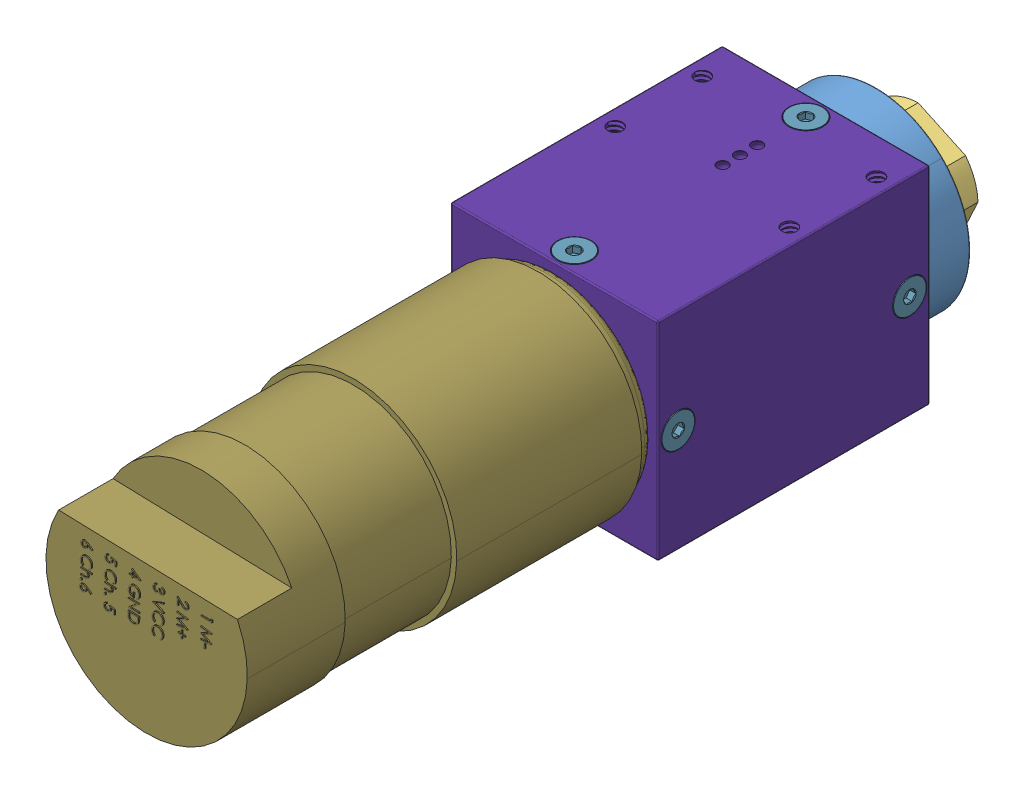
SolidWorks assembly am-3643 NeveRest Sport, 104-1 with Motor, configuration Default. Lengths in mm.
Overall size (48.85 48.85 145.31).
41 component instances, 19 part files, 0 mates.
Components (placement in the parent):
- am-3643 NeveRest Sport, 104-1 with Motor(2)^am-3643 NeveRest Sport, 104-1 with Motor-1: am-3643 NeveRest Sport, 104-1 with Motor(2)^am-3643 NeveRest Sport, 104-1 with Motor [Default] at origin size (48.85 48.85 145.31) (virtual)
  - dv-XXXX Output Plug - 550 Sport^am-3643 NeveRest Sport, 104-1 with Motor(2)_am-3643 NeveRest Sport, 104-1 with Motor-1: dv-XXXX Output Plug - 550 Sport^am-3643 NeveRest Sport, 104-1 with Motor(2)_am-3643 NeveRest Sport, 104-1 with Motor [Default] at (30.7788 -45.9281 37.6212) x (-0.707107 -0.707107 0) z (0 0 1) size (34.54 34.54 34.87) (virtual)
    - dv-XXXX Output Plug with orbital bolt circle^dv-XXXX Output Plug - 550 Sport_am-3643 NeveRest Sport, 104-1 with Motor(2)_am-3643 NeveRest Sport, 104-1 with Motor-1: dv-XXXX Output Plug with orbital bolt circle^dv-XXXX Output Plug - 550 Sport_am-3643 NeveRest Sport, 104-1 with Motor(2)_am-3643 NeveRest Sport, 104-1 with Motor [Default] at (-7.0244 -4.5434 5.3964) size (34.54 34.54 17.78) (virtual)
    - BALL BEARING_5972K154^dv-XXXX Output Plug - 550 Sport_am-3643 NeveRest Sport, 104-1 with Motor(2)_am-3643 NeveRest Sport, 104-1 with Motor-1: BALL BEARING_5972K154^dv-XXXX Output Plug - 550 Sport_am-3643 NeveRest Sport, 104-1 with Motor(2)_am-3643 NeveRest Sport, 104-1 with Motor [Default] at (-7.0244 -4.5434 -0.8666) size (21 21 5) (virtual)
    - BALL BEARING_5972K154^dv-XXXX Output Plug - 550 Sport_am-3643 NeveRest Sport, 104-1 with Motor(2)_am-3643 NeveRest Sport, 104-1 with Motor-2: BALL BEARING_5972K154^dv-XXXX Output Plug - 550 Sport_am-3643 NeveRest Sport, 104-1 with Motor(2)_am-3643 NeveRest Sport, 104-1 with Motor [Default] at (-7.0244 -4.5434 10.1354) size (21 21 5) (virtual)
    - Nub Shaft^dv-XXXX Output Plug - 550 Sport_am-3643 NeveRest Sport, 104-1 with Motor(2)_am-3643 NeveRest Sport, 104-1 with Motor-1: Nub Shaft^dv-XXXX Output Plug - 550 Sport_am-3643 NeveRest Sport, 104-1 with Motor(2)_am-3643 NeveRest Sport, 104-1 with Motor [Default] at (-7.0244 -4.5434 20.2536) x (-0.939267 -0.343187 0) z (0.343187 -0.939267 0) size (19.05 34.87 19.05) (virtual)
  - dv-XXXX Carrier Stage 4-1 Planet, 5-1 Sun - 550 Sport^am-3643 NeveRest Sport, 104-1 with Motor(2)_am-3643 NeveRest Sport, 104-1 with Motor-1: dv-XXXX Carrier Stage 4-1 Planet, 5-1 Sun - 550 Sport^am-3643 NeveRest Sport, 104-1 with Motor(2)_am-3643 NeveRest Sport, 104-1 with Motor [Default] at (63.7059 -27.5277 100.4568) x (0.941837 -0.336071 0) z (-0.336071 -0.941837 0) size (29.23 15.47 28.59) (virtual)
    - am-2892+15T+pinion+3.2mm+bore^dv-XXXX Carrier Stage 4-1 Planet, 5-1 Sun - 550 Sport_am-3643 NeveRest Sport, 104-1 with Motor(2)_am-3643 NeveRest Sport, 104-1 with Motor-1: am-2892+15T+pinion+3.2mm+bore^dv-XXXX Carrier Stage 4-1 Planet, 5-1 Sun - 550 Sport_am-3643 NeveRest Sport, 104-1 with Motor(2)_am-3643 NeveRest Sport, 104-1 with Motor [Default] at (-25.9249 -17.3194 11.1026) x (0 -1 0) z (0.056322 0 -0.998413) size (5.31 10.12 10.18) (virtual)
    - am-2892+15T+pinion+3.2mm+bore^dv-XXXX Carrier Stage 4-1 Planet, 5-1 Sun - 550 Sport_am-3643 NeveRest Sport, 104-1 with Motor(2)_am-3643 NeveRest Sport, 104-1 with Motor-2: am-2892+15T+pinion+3.2mm+bore^dv-XXXX Carrier Stage 4-1 Planet, 5-1 Sun - 550 Sport_am-3643 NeveRest Sport, 104-1 with Motor(2)_am-3643 NeveRest Sport, 104-1 with Motor [Default] at (-16.9249 -17.3194 20.1026) x (0 -1 0) z (-0.169038 0 -0.98561) size (5.31 10.12 10.18) (virtual)
    - am-2892+15T+pinion+3.2mm+bore^dv-XXXX Carrier Stage 4-1 Planet, 5-1 Sun - 550 Sport_am-3643 NeveRest Sport, 104-1 with Motor(2)_am-3643 NeveRest Sport, 104-1 with Motor-3: am-2892+15T+pinion+3.2mm+bore^dv-XXXX Carrier Stage 4-1 Planet, 5-1 Sun - 550 Sport_am-3643 NeveRest Sport, 104-1 with Motor(2)_am-3643 NeveRest Sport, 104-1 with Motor [Default] at (-25.9249 -17.3194 29.1026) x (0 -1 0) z (-0.027474 0 -0.999623) size (5.31 10.12 10.18) (virtual)
    - am-2892+15T+pinion+3.2mm+bore^dv-XXXX Carrier Stage 4-1 Planet, 5-1 Sun - 550 Sport_am-3643 NeveRest Sport, 104-1 with Motor(2)_am-3643 NeveRest Sport, 104-1 with Motor-4: am-2892+15T+pinion+3.2mm+bore^dv-XXXX Carrier Stage 4-1 Planet, 5-1 Sun - 550 Sport_am-3643 NeveRest Sport, 104-1 with Motor(2)_am-3643 NeveRest Sport, 104-1 with Motor [Default] at (-34.9249 -17.3194 20.1026) x (0 -1 0) z (-0.064746 0 -0.997902) size (5.31 10.12 10.18) (virtual)
    - dv-XXXX - Carrier Plate 4-1 Planet, 5-1 Sun^dv-XXXX Carrier Stage 4-1 Planet, 5-1 Sun - 550 Sport_am-3643 NeveRest Sport, 104-1 with Motor(2)_am-3643 NeveRest Sport, 104-1 with Motor-1: dv-XXXX - Carrier Plate 4-1 Planet, 5-1 Sun^dv-XXXX Carrier Stage 4-1 Planet, 5-1 Sun - 550 Sport_am-3643 NeveRest Sport, 104-1 with Motor(2)_am-3643 NeveRest Sport, 104-1 with Motor [Default] at (-25.9249 -27.154 20.1026) size (25.04 10 25.04) (virtual)
    - 11T+pinion+3.2mm+bore^dv-XXXX Carrier Stage 4-1 Planet, 5-1 Sun - 550 Sport_am-3643 NeveRest Sport, 104-1 with Motor(2)_am-3643 NeveRest Sport, 104-1 with Motor-1: 11T+pinion+3.2mm+bore^dv-XXXX Carrier Stage 4-1 Planet, 5-1 Sun - 550 Sport_am-3643 NeveRest Sport, 104-1 with Motor(2)_am-3643 NeveRest Sport, 104-1 with Motor [Default] at (-25.9249 -22.6277 20.1026) x (0 -1 0) z (-0.988725 0 -0.149745) size (10 7.67 7.74) (virtual)
  - dv-XXXX Carrier Stage 5-1 Planet, 5-1 Sun^am-3643 NeveRest Sport, 104-1 with Motor(2)_am-3643 NeveRest Sport, 104-1 with Motor-1: dv-XXXX Carrier Stage 5-1 Planet, 5-1 Sun^am-3643 NeveRest Sport, 104-1 with Motor(2)_am-3643 NeveRest Sport, 104-1 with Motor [Default] at (6.8131 -34.6705 55.7021) x (-0.996841 0.079427 0) z (0.079427 0.996841 0) size (29.78 15.47 28.75) (virtual)
    - dv-XXXX - Carrier Plate 5-1 Planet, 5-1 Sun^dv-XXXX Carrier Stage 5-1 Planet, 5-1 Sun_am-3643 NeveRest Sport, 104-1 with Motor(2)_am-3643 NeveRest Sport, 104-1 with Motor-1: dv-XXXX - Carrier Plate 5-1 Planet, 5-1 Sun^dv-XXXX Carrier Stage 5-1 Planet, 5-1 Sun_am-3643 NeveRest Sport, 104-1 with Motor(2)_am-3643 NeveRest Sport, 104-1 with Motor [Default] at (-26.6144 7.6007 0.9439) size (25.04 10 25.04) (virtual)
    - 17T+pinion+3.2mm+bore^dv-XXXX Carrier Stage 5-1 Planet, 5-1 Sun_am-3643 NeveRest Sport, 104-1 with Motor(2)_am-3643 NeveRest Sport, 104-1 with Motor-1: 17T+pinion+3.2mm+bore^dv-XXXX Carrier Stage 5-1 Planet, 5-1 Sun_am-3643 NeveRest Sport, 104-1 with Motor(2)_am-3643 NeveRest Sport, 104-1 with Motor [Default] at (-35.0144 12.127 0.9439) x (0 1 0) z (-0.112997 0 0.993595) size (5.31 11.33 11.37) (virtual)
    - 17T+pinion+3.2mm+bore^dv-XXXX Carrier Stage 5-1 Planet, 5-1 Sun_am-3643 NeveRest Sport, 104-1 with Motor(2)_am-3643 NeveRest Sport, 104-1 with Motor-2: 17T+pinion+3.2mm+bore^dv-XXXX Carrier Stage 5-1 Planet, 5-1 Sun_am-3643 NeveRest Sport, 104-1 with Motor(2)_am-3643 NeveRest Sport, 104-1 with Motor [Default] at (-26.6144 12.127 9.3439) x (0 1 0) z (0.065842 0 0.99783) size (5.31 11.33 11.37) (virtual)
    - 17T+pinion+3.2mm+bore^dv-XXXX Carrier Stage 5-1 Planet, 5-1 Sun_am-3643 NeveRest Sport, 104-1 with Motor(2)_am-3643 NeveRest Sport, 104-1 with Motor-3: 17T+pinion+3.2mm+bore^dv-XXXX Carrier Stage 5-1 Planet, 5-1 Sun_am-3643 NeveRest Sport, 104-1 with Motor(2)_am-3643 NeveRest Sport, 104-1 with Motor [Default] at (-26.6144 12.127 -7.4561) x (0 1 0) z (0.038378 0 0.999263) size (5.31 11.33 11.37) (virtual)
    - 17T+pinion+3.2mm+bore^dv-XXXX Carrier Stage 5-1 Planet, 5-1 Sun_am-3643 NeveRest Sport, 104-1 with Motor(2)_am-3643 NeveRest Sport, 104-1 with Motor-4: 17T+pinion+3.2mm+bore^dv-XXXX Carrier Stage 5-1 Planet, 5-1 Sun_am-3643 NeveRest Sport, 104-1 with Motor(2)_am-3643 NeveRest Sport, 104-1 with Motor [Default] at (-18.2144 12.127 0.9439) x (0 1 0) z (0.205012 0 0.978759) size (5.31 11.33 11.37) (virtual)
    - 13T+pinion+3.2mm+bore^dv-XXXX Carrier Stage 5-1 Planet, 5-1 Sun_am-3643 NeveRest Sport, 104-1 with Motor(2)_am-3643 NeveRest Sport, 104-1 with Motor-1: 13T+pinion+3.2mm+bore^dv-XXXX Carrier Stage 5-1 Planet, 5-1 Sun_am-3643 NeveRest Sport, 104-1 with Motor(2)_am-3643 NeveRest Sport, 104-1 with Motor [Default] at (-26.6144 12.127 0.9439) x (0 -1 0) z (-0.984718 0 0.174154) size (10 8.9 8.96) (virtual)
  - dv-XXXX Carrier Stage 5-1 Planet, 0.3125 hex output^am-3643 NeveRest Sport, 104-1 with Motor(2)_am-3643 NeveRest Sport, 104-1 with Motor-1: dv-XXXX Carrier Stage 5-1 Planet, 0.3125 hex output^am-3643 NeveRest Sport, 104-1 with Motor(2)_am-3643 NeveRest Sport, 104-1 with Motor [Default] at (38.8348 -52.014 37.7173) x (0.574594 -0.818439 0) z (-0.818439 -0.574594 0) size (30.46 10 28.73) (virtual)
    - dv-XXXX - Carrier Plate 5-1 Planet, 0.3125 hex output^dv-XXXX Carrier Stage 5-1 Planet, 0.3125 hex output_am-3643 NeveRest Sport, 104-1 with Motor(2)_am-3643 NeveRest Sport, 104-1 with Motor-1: dv-XXXX - Carrier Plate 5-1 Planet, 0.3125 hex output^dv-XXXX Carrier Stage 5-1 Planet, 0.3125 hex output_am-3643 NeveRest Sport, 104-1 with Motor(2)_am-3643 NeveRest Sport, 104-1 with Motor [Default] at (-16.3468 15.5854 -4.8585) size (25.04 10 25.04) (virtual)
    - 17T+pinion+3.2mm+bore^dv-XXXX Carrier Stage 5-1 Planet, 0.3125 hex output_am-3643 NeveRest Sport, 104-1 with Motor(2)_am-3643 NeveRest Sport, 104-1 with Motor-1: 17T+pinion+3.2mm+bore^dv-XXXX Carrier Stage 5-1 Planet, 0.3125 hex output_am-3643 NeveRest Sport, 104-1 with Motor(2)_am-3643 NeveRest Sport, 104-1 with Motor [Default] at (-24.7468 20.1117 -4.8585) x (0 1 0) z (0.867721 0 0.497051) size (5.31 11.33 11.37) (virtual)
    - 17T+pinion+3.2mm+bore^dv-XXXX Carrier Stage 5-1 Planet, 0.3125 hex output_am-3643 NeveRest Sport, 104-1 with Motor(2)_am-3643 NeveRest Sport, 104-1 with Motor-2: 17T+pinion+3.2mm+bore^dv-XXXX Carrier Stage 5-1 Planet, 0.3125 hex output_am-3643 NeveRest Sport, 104-1 with Motor(2)_am-3643 NeveRest Sport, 104-1 with Motor [Default] at (-16.3468 20.1117 3.5415) x (0 1 0) z (-0.061129 0 0.99813) size (5.31 11.33 11.37) (virtual)
    - 17T+pinion+3.2mm+bore^dv-XXXX Carrier Stage 5-1 Planet, 0.3125 hex output_am-3643 NeveRest Sport, 104-1 with Motor(2)_am-3643 NeveRest Sport, 104-1 with Motor-3: 17T+pinion+3.2mm+bore^dv-XXXX Carrier Stage 5-1 Planet, 0.3125 hex output_am-3643 NeveRest Sport, 104-1 with Motor(2)_am-3643 NeveRest Sport, 104-1 with Motor [Default] at (-16.3468 20.1117 -13.2585) x (0 1 0) z (0.038378 0 0.999263) size (5.31 11.33 11.37) (virtual)
    - 17T+pinion+3.2mm+bore^dv-XXXX Carrier Stage 5-1 Planet, 0.3125 hex output_am-3643 NeveRest Sport, 104-1 with Motor(2)_am-3643 NeveRest Sport, 104-1 with Motor-4: 17T+pinion+3.2mm+bore^dv-XXXX Carrier Stage 5-1 Planet, 0.3125 hex output_am-3643 NeveRest Sport, 104-1 with Motor(2)_am-3643 NeveRest Sport, 104-1 with Motor [Default] at (-7.9468 20.1117 -4.8585) x (0 1 0) z (0.040503 0 0.999179) size (5.31 11.33 11.37) (virtual)
  - neveRest+15T+pinion^am-3643 NeveRest Sport, 104-1 with Motor(2)_am-3643 NeveRest Sport, 104-1 with Motor-1: neveRest+15T+pinion^am-3643 NeveRest Sport, 104-1 with Motor(2)_am-3643 NeveRest Sport, 104-1 with Motor [Default] at (-29.3619 -57.8483 143.121) x (-0.999543 0.030232 0) z (0 0 -1) size (38 38 89.79) (virtual)
    - am-3104 NeveRest Motor^neveRest+15T+pinion_am-3643 NeveRest Sport, 104-1 with Motor(2)_am-3643 NeveRest Sport, 104-1 with Motor-1: am-3104 NeveRest Motor^neveRest+15T+pinion_am-3643 NeveRest Sport, 104-1 with Motor(2)_am-3643 NeveRest Sport, 104-1 with Motor [Default] at (-61.259 21.9619 50.009) size (38 38 85.19) (virtual)
    - 15T+pinion+3.2mm+bore+motor^neveRest+15T+pinion_am-3643 NeveRest Sport, 104-1 with Motor(2)_am-3643 NeveRest Sport, 104-1 with Motor-1: 15T+pinion+3.2mm+bore+motor^neveRest+15T+pinion_am-3643 NeveRest Sport, 104-1 with Motor(2)_am-3643 NeveRest Sport, 104-1 with Motor [Default] at (-61.259 21.9619 54.7947) x (0 0 1) z (-0.930076 -0.367368 0) size (9.81 10.12 10.18) (virtual)
  - 91294A126_BLACK ALLOY STEEL FLAT-HEAD SOCKET CAP SCREW_91294A126^am-3643 NeveRest Sport, 104-1 with Motor(2)_am-3643 NeveRest Sport, 104-1 with Motor-1: 91294A126_BLACK ALLOY STEEL FLAT-HEAD SOCKET CAP SCREW_91294A126^am-3643 NeveRest Sport, 104-1 with Motor(2)_am-3643 NeveRest Sport, 104-1 with Motor [Default] at (13.433 -37.7484 46.9556) x (0 0 1) z (-1 0 0) size (6 6 6.01) (virtual)
  - Thrust Washer^am-3643 NeveRest Sport, 104-1 with Motor(2)_am-3643 NeveRest Sport, 104-1 with Motor-1: Thrust Washer^am-3643 NeveRest Sport, 104-1 with Motor(2)_am-3643 NeveRest Sport, 104-1 with Motor [Default] at (32.533 -37.7484 84.9184) x (0.422278 0.906466 0) z (0 0 -1) size (28.45 28.45 0.51) (virtual)
  - dv-XXXX Motor Mount Plug^am-3643 NeveRest Sport, 104-1 with Motor(2)_am-3643 NeveRest Sport, 104-1 with Motor-1: dv-XXXX Motor Mount Plug^am-3643 NeveRest Sport, 104-1 with Motor(2)_am-3643 NeveRest Sport, 104-1 with Motor [Default] at (32.533 -37.7484 93.1201) x (-0.707107 0.707107 0) z (0 0 -1) size (30.99 30.99 8.13) (virtual)
  - 91294A126_BLACK ALLOY STEEL FLAT-HEAD SOCKET CAP SCREW_91294A126^am-3643 NeveRest Sport, 104-1 with Motor(2)_am-3643 NeveRest Sport, 104-1 with Motor-2: 91294A126_BLACK ALLOY STEEL FLAT-HEAD SOCKET CAP SCREW_91294A126^am-3643 NeveRest Sport, 104-1 with Motor(2)_am-3643 NeveRest Sport, 104-1 with Motor [Default] at (32.533 -18.6484 89.5006) x (0.466078 0 0.884744) z (0 1 0) size (6 6 6.01) (virtual)
  - 91294A126_BLACK ALLOY STEEL FLAT-HEAD SOCKET CAP SCREW_91294A126^am-3643 NeveRest Sport, 104-1 with Motor(2)_am-3643 NeveRest Sport, 104-1 with Motor-3: 91294A126_BLACK ALLOY STEEL FLAT-HEAD SOCKET CAP SCREW_91294A126^am-3643 NeveRest Sport, 104-1 with Motor(2)_am-3643 NeveRest Sport, 104-1 with Motor [Default] at (32.533 -18.6484 46.9556) x (0.982767 0 0.184847) z (0 1 0) size (6 6 6.01) (virtual)
  - 91294A126_BLACK ALLOY STEEL FLAT-HEAD SOCKET CAP SCREW_91294A126^am-3643 NeveRest Sport, 104-1 with Motor(2)_am-3643 NeveRest Sport, 104-1 with Motor-4: 91294A126_BLACK ALLOY STEEL FLAT-HEAD SOCKET CAP SCREW_91294A126^am-3643 NeveRest Sport, 104-1 with Motor(2)_am-3643 NeveRest Sport, 104-1 with Motor [Default] at (13.433 -37.7484 89.5006) x (0 0 1) z (-1 0 0) size (6 6 6.01) (virtual)
  - 91294A126_BLACK ALLOY STEEL FLAT-HEAD SOCKET CAP SCREW_91294A126^am-3643 NeveRest Sport, 104-1 with Motor(2)_am-3643 NeveRest Sport, 104-1 with Motor-5: 91294A126_BLACK ALLOY STEEL FLAT-HEAD SOCKET CAP SCREW_91294A126^am-3643 NeveRest Sport, 104-1 with Motor(2)_am-3643 NeveRest Sport, 104-1 with Motor [Default] at (51.633 -37.7484 46.9556) x (0 -0.421523 0.906818) z (1 0 0) size (6 6 6.01) (virtual)
  - 91294A126_BLACK ALLOY STEEL FLAT-HEAD SOCKET CAP SCREW_91294A126^am-3643 NeveRest Sport, 104-1 with Motor(2)_am-3643 NeveRest Sport, 104-1 with Motor-6: 91294A126_BLACK ALLOY STEEL FLAT-HEAD SOCKET CAP SCREW_91294A126^am-3643 NeveRest Sport, 104-1 with Motor(2)_am-3643 NeveRest Sport, 104-1 with Motor [Default] at (51.633 -37.7484 89.5006) x (0 -0.712248 -0.701928) z (1 0 0) size (6 6 6.01) (virtual)
  - dv-XXXX - 3 Stage 550 Sport Ring Gear Housing^am-3643 NeveRest Sport, 104-1 with Motor(2)_am-3643 NeveRest Sport, 104-1 with Motor-1: dv-XXXX - 3 Stage 550 Sport Ring Gear Housing^am-3643 NeveRest Sport, 104-1 with Motor(2)_am-3643 NeveRest Sport, 104-1 with Motor [Default] at (13.483 -56.7984 68.2281) size (38.1 38.1 49.91) (virtual)
  - 10-32 x 0.25 Set Screw Cup Point^am-3643 NeveRest Sport, 104-1 with Motor(2)_am-3643 NeveRest Sport, 104-1 with Motor-1: 10-32 x 0.25 Set Screw Cup Point^am-3643 NeveRest Sport, 104-1 with Motor(2)_am-3643 NeveRest Sport, 104-1 with Motor [Default] at (42.0774 -42.1846 29.5006) x (-0.906832 0.421492 0) z (0.0498 0.107144 0.992995) size (6.35 4.83 4.83) (virtual)
  - M3x0.5x6mm SHCS_91290A111^am-3643 NeveRest Sport, 104-1 with Motor(2)_am-3643 NeveRest Sport, 104-1 with Motor-1: M3x0.5x6mm SHCS_91290A111^am-3643 NeveRest Sport, 104-1 with Motor(2)_am-3643 NeveRest Sport, 104-1 with Motor [Default] at (23.6942 -46.5873 96.1483) size (5.5 5.5 9.01) (virtual)
  - M3x0.5x6mm SHCS_91290A111^am-3643 NeveRest Sport, 104-1 with Motor(2)_am-3643 NeveRest Sport, 104-1 with Motor-2: M3x0.5x6mm SHCS_91290A111^am-3643 NeveRest Sport, 104-1 with Motor(2)_am-3643 NeveRest Sport, 104-1 with Motor [Default] at (41.3718 -28.9096 96.1483) size (5.5 5.5 9.01) (virtual)
